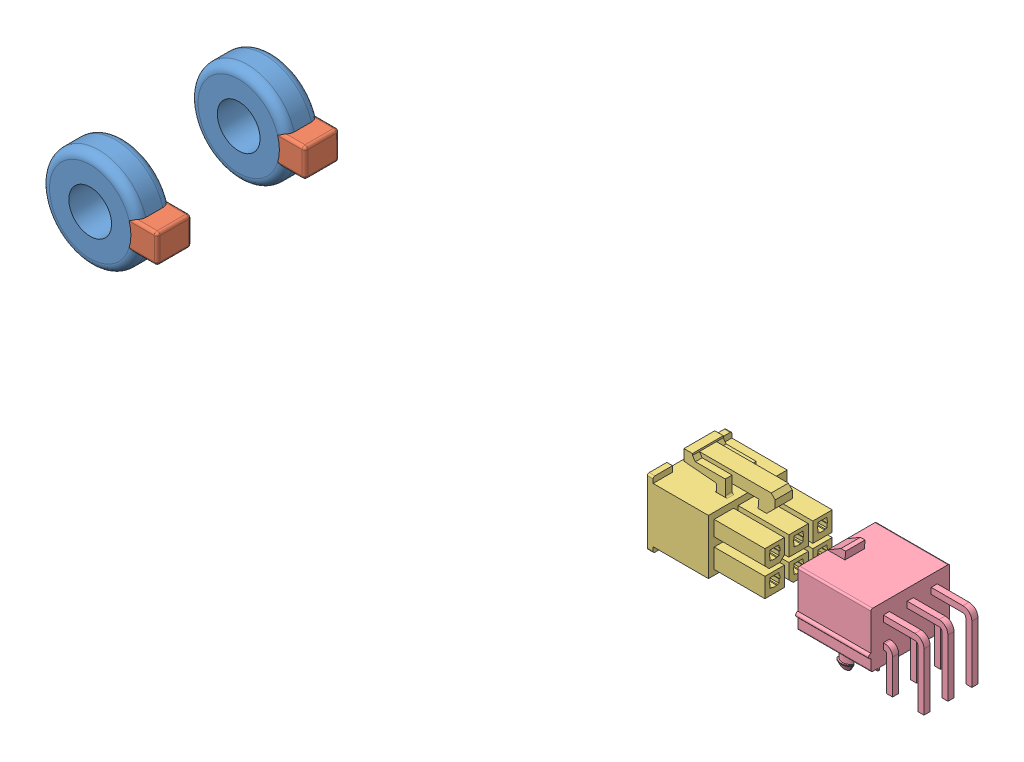
SolidWorks assembly CTAssem, configuration Default. Lengths in mm.
Overall size (139.84 27.67 31.24).
6 component instances, 4 part files, 10 mates.
Components (placement in the parent):
- CTTorus-1: CTTorus [Default] at (-125.9575 17.9861 63.9805) size (17.25 17.25 6)
- CTBlock-1: CTBlock [Default] at (-116.8325 17.9861 63.9805) size (5 5 6)
- 039012060-1: 039012060 [Default] at (-31.1434 7.7409 72.5459) x (0 0 -1) z (1 0 0) size (13.8 14.4 19.6)
- 026013116-1: 026013116 [Default] at (-15.4617 2.5409 72.5459) x (0 0 1) z (-1 0 0) size (14.2 15 19.94)
- CTTorus-2: CTTorus [Default] at (-126.7443 17.2362 89.2254) size (17.25 17.25 6)
- CTBlock-2: CTBlock [Default] at (-117.4943 17.2362 89.2254) size (5 5 6)
Mates (geometry in assembly coordinates):
- Width1: width anti-aligned: plane of CTTorus-1 through (-125.9575 17.9861 60.9805) normal (0 0 -1); plane of CTTorus-1 through (-125.9575 17.9861 66.9805) normal (0 0 1); plane of CTBlock-1 through (-116.8325 17.9861 66.9805) normal (0 0 1); plane of CTBlock-1 through (-116.8325 17.9861 60.9805) normal (0 0 -1)
- Distance1: distance = 3 mm aligned: plane of CTBlock-1 through (-114.3325 15.4861 66.9805) normal (1 0 0); cylinder of CTTorus-1 through (-125.9575 17.9861 66.9805) axis (0 0 -1) radius 8.625
- Parallel2: parallel anti-aligned: plane of 039012060-1 through (-31.1434 12.5409 79.4459) normal (1 0 0); plane of 026013116-1 through (-15.4617 2.5409 72.5459) normal (-1 0 0)
- Parallel3: parallel aligned: plane of 039012060-1 through (-31.1434 7.7409 79.4459) normal (0 0 1); plane of 026013116-1 through (-15.4617 12.5409 79.4459) normal (0 0 1)
- Coincident5: coincident aligned: plane of 039012060-1 through (-41.8434 12.5409 79.4459) normal (0 1 0); plane of 026013116-1 through (-15.4617 12.5409 65.6459) normal (0 1 0)
- Coincident6: coincident aligned: plane of 039012060-1 through (-31.1434 7.7409 79.4459) normal (0 0 1); plane of 026013116-1 through (-15.4617 12.5409 79.4459) normal (0 0 1)
- Width3: width anti-aligned: plane of CTBlock-1 through (-119.3325 20.4861 66.9805) normal (0 1 0); plane of CTBlock-1 through (-119.3325 15.4861 66.9805) normal (0 -1 0); cylinder of CTTorus-1 through (-125.9575 17.9861 66.9805) axis (0 0 -1) radius 8.625
- Distance3: distance = 3 mm anti-aligned: plane of CTBlock-2 through (-119.9943 14.7362 92.2254) normal (-1 0 0); cylinder of CTTorus-2 through (-126.7443 17.2362 92.2254) axis (0 0 -1) radius 3.75
- Coincident7: coincident aligned: plane of CTTorus-2 through (-126.7443 17.2362 86.2254) normal (0 0 -1); plane of CTBlock-2 through (-117.4943 17.2362 86.2254) normal (0 0 -1)
- Width4: width anti-aligned: plane of CTBlock-2 through (-119.9943 19.7362 92.2254) normal (0 1 0); plane of CTBlock-2 through (-119.9943 14.7362 92.2254) normal (0 -1 0); cylinder of CTTorus-2 through (-126.7443 17.2362 92.2254) axis (0 0 -1) radius 8.625
